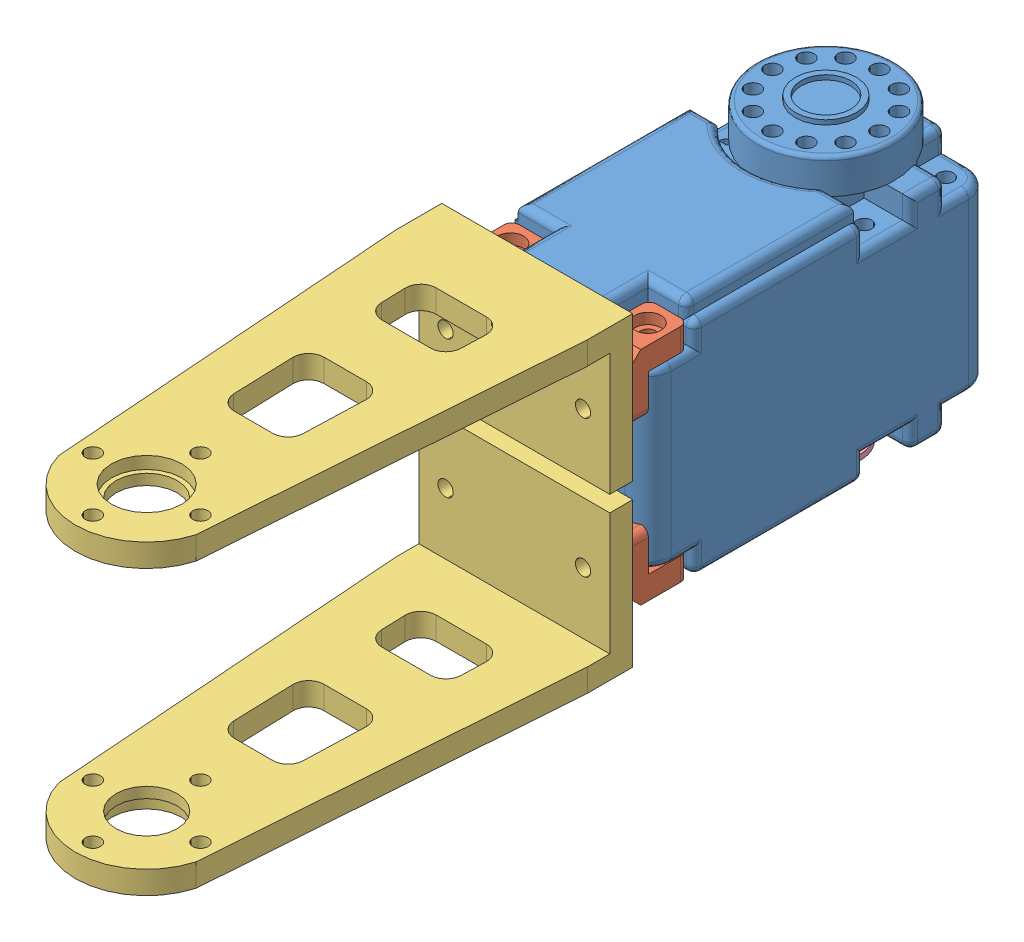
SolidWorks assembly Thigh, configuration Default. Lengths in mm.
Overall size (25 40.1 107.98).
8 component instances, 4 part files, 18 mates.
Components (placement in the parent):
- herkulex_motor-2: herkulex_motor [Default] at (23.0079 4.9835 32.2152) size (24 34.2 45)
- L joint-5: L joint [Default] at (29.4579 30.9835 54.2152) x (0 -1 0) z (0 0 1) size (8.2 5.1 8.2)
- upper leg-2: upper leg [Default] at (23.0079 -14.0665 160.3647) x (0 1 0) z (1 0 0) size (19 60.48 25)
- L joint-6: L joint [Default] at (11.4579 30.9835 54.2152) x (0 -1 0) z (0 0 1) size (8.2 5.1 8.2)
- L joint-7: L joint [Default] at (34.5579 7.9835 54.2152) x (0 1 0) z (0 0 1) size (8.2 5.1 8.2)
- L joint-8: L joint [Default] at (16.5579 7.9835 54.2152) x (0 1 0) z (0 0 1) size (8.2 5.1 8.2)
- upper leg-3: upper leg [Default] at (23.0079 53.0335 160.3647) x (0 -1 0) z (-1 0 0) size (19 60.48 25)
- support-1: support [Default] at (23.0079 5.4835 19.4152) x (0 -1 0) z (-0.265948 0 0.963987) size (5.5 9 9)
Mates (geometry in assembly coordinates):
- Concentric5: concentric anti-aligned: cylinder of herkulex_motor-2 through (32.0079 4.9835 51.7152) axis (0 1 0) radius 1; cylinder of L joint-5 through (32.0079 36.0835 51.7152) axis (0 -1 0) radius 1
- Coincident9: coincident anti-aligned: plane of herkulex_motor-2 through (23.0079 30.9835 32.2152) normal (0 1 0); plane of L joint-5 through (34.5579 30.9835 54.2152) normal (0 -1 0)
- Concentric6: concentric anti-aligned: cylinder of herkulex_motor-2 through (14.0079 4.9835 51.7152) axis (0 1 0) radius 1; cylinder of L joint-6 through (14.0079 36.0835 51.7152) axis (0 -1 0) radius 1
- Coincident10: coincident anti-aligned: plane of herkulex_motor-2 through (23.0079 30.9835 32.2152) normal (0 1 0); plane of L joint-6 through (16.5579 30.9835 54.2152) normal (0 -1 0)
- Concentric7: concentric anti-aligned: cylinder of herkulex_motor-2 through (32.0079 4.9835 51.7152) axis (0 1 0) radius 1; cylinder of L joint-7 through (32.0079 6.3835 51.7152) axis (0 -1 0) radius 1.7
- Parallel5: parallel aligned: plane of herkulex_motor-2 through (11.0079 35.9835 54.7152) normal (0 0 1); plane of L joint-7 through (29.4579 4.9835 57.2152) normal (0 0 1)
- Coincident12: coincident anti-aligned: plane of herkulex_motor-2 through (23.0079 7.9835 32.2152) normal (0 -1 0); plane of L joint-7 through (29.4579 7.9835 54.2152) normal (0 1 0)
- Concentric8: concentric aligned: cylinder of herkulex_motor-2 through (14.0079 4.9835 51.7152) axis (0 1 0) radius 1; cylinder of L joint-8 through (14.0079 2.8835 51.7152) axis (0 1 0) radius 1
- Coincident13: coincident anti-aligned: plane of herkulex_motor-2 through (23.0079 7.9835 32.2152) normal (0 -1 0); plane of L joint-8 through (11.4579 7.9835 54.2152) normal (0 1 0)
- Parallel6: parallel aligned: plane of herkulex_motor-2 through (11.0079 35.9835 54.7152) normal (0 0 1); plane of L joint-8 through (11.4579 4.9835 57.2152) normal (0 0 1)
- Coincident15: coincident anti-aligned: plane of upper leg-2 through (10.5079 61.6219 57.2152) normal (0 0 -1); plane of L joint-7 through (29.4579 4.9835 57.2152) normal (0 0 1)
- Coincident16: coincident anti-aligned: cylinder of upper leg-2 through (32.0079 10.4835 48.7152) axis (0 0 1) radius 1; circle of L joint-7
- Parallel7: parallel aligned: plane of herkulex_motor-2 through (23.0079 4.9835 32.2152) normal (0 -1 0); plane of upper leg-2 through (23.0079 -0.5665 160.3647) normal (0 -1 0)
- Coincident18: coincident anti-aligned: plane of L joint-5 through (34.5579 33.9835 57.2152) normal (0 0 1); plane of upper leg-3 through (35.5079 -22.6549 57.2152) normal (0 0 -1)
- Concentric9: concentric anti-aligned: cylinder of L joint-5 through (32.0079 28.4835 59.3152) axis (0 0 -1) radius 1; cylinder of upper leg-3 through (32.0079 28.4835 48.7152) axis (0 0 1) radius 1
- Parallel8: parallel aligned: plane of herkulex_motor-2 through (23.0079 35.9835 32.2152) normal (0 1 0); plane of upper leg-3 through (23.0079 39.5335 160.3647) normal (0 1 0)
- Coincident19: coincident: plane of herkulex_motor-2 through (23.0079 5.4835 19.4152) normal (0 -1 0); plane of support-1 through (23.0079 5.4835 19.4152) normal (0 1 0)
- Concentric10: concentric aligned: cylinder of herkulex_motor-2 through (23.0079 14.9835 19.4152) axis (0 -1 0) radius 1.475; cylinder of support-1 through (23.0079 1.9835 19.4152) axis (0 -1 0) radius 2.7
